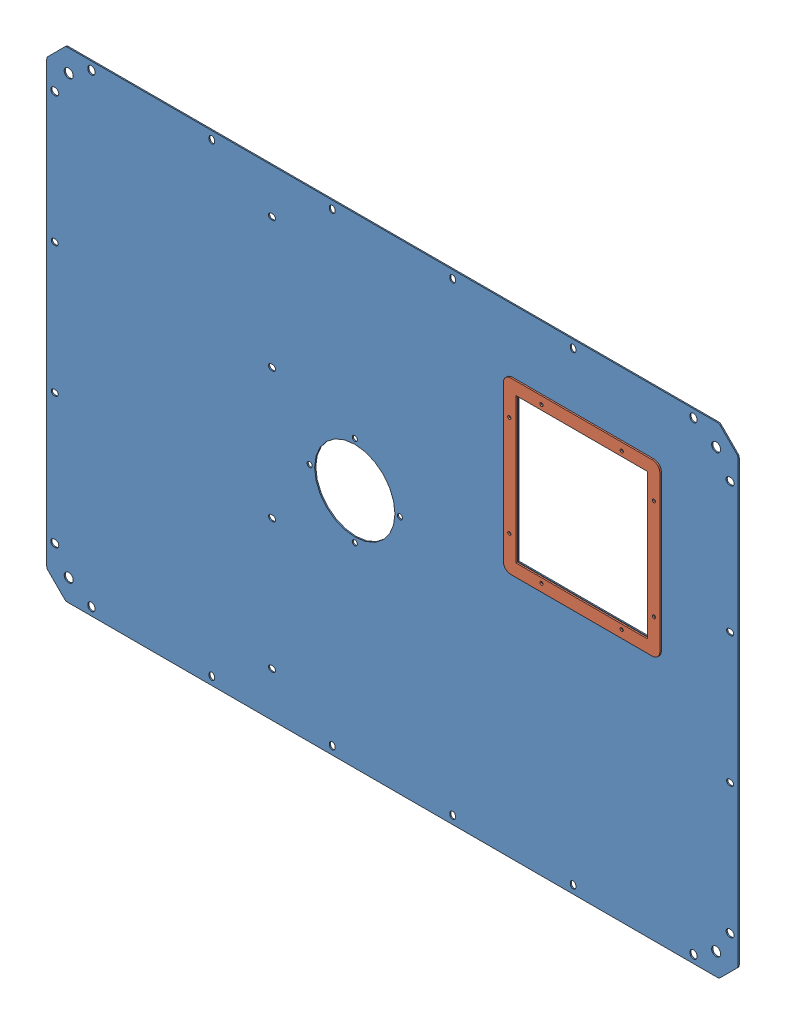
SolidWorks assembly 機體上罩蓋板, configuration 預設. Lengths in mm.
Overall size (1378 958 5.3).
2 component instances, 2 part files, 3 mates.
Components (placement in the parent):
- LB-A54A-02-21-1: LB-A54A-02-21 [預設] at (-4377.1325 -10659.9752 -1.15) size (1378 958 2.3)
- FE2100LZ-54-92-1: FE2100LZ-54-92 [預設] at (-5843.4685 -9987.5521 1.15) size (312.1 339 3)
Mates (geometry in assembly coordinates):
- 重合/共線/共點1: coincident: plane of LB-A54A-02-21-1 through (-710.3937 480.0562 1.15) normal (0 0 1); plane of FE2100LZ-54-92-1 through (176.2846 37.8062 1.15) normal (0 0 -1)
- 重合/共線/共點2: coincident: line of LB-A54A-02-21-1 through (176.2846 361.8062 -1.15) axis (1 0 0); plane of FE2100LZ-54-92-1 through (458.3846 361.8062 4.15) normal (0 1 0)
- 重合/共線/共點3: coincident: line of LB-A54A-02-21-1 through (473.3846 346.8062 -1.15) axis (0 -1 0); plane of FE2100LZ-54-92-1 through (473.3846 37.8062 4.15) normal (1 0 0)
